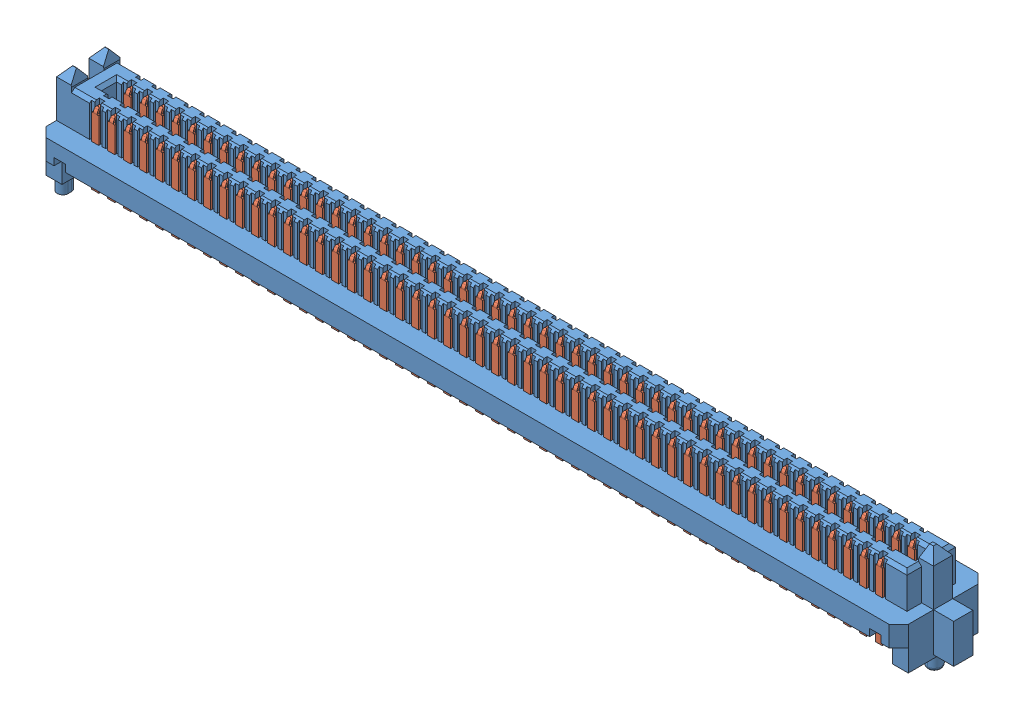
SolidWorks assembly Assem3, configuration Default. Lengths in mm.
Overall size (70.08 8.38 7.06).
5 component instances, 4 part files, 3 mates.
Components (placement in the parent):
- SEAM_50_03_5_L_04_2_A_K_TR-1: SEAM_50_03_5_L_04_2_A_K_TR [Default] at (0 3.3528 0) size (70.08 8.38 7.06)
  - _SEAM_50_03_5_L_04_1_A_K_TR_body_2-1: _SEAM_50_03_5_L_04_1_A_K_TR_body_2 [Default] at origin size (70.08 8.38 7.06)
  - _SEAM_50_03_5_L_04_1_A_K_TR_conn_4-1: _SEAM_50_03_5_L_04_1_A_K_TR_conn_4 [Default] at origin size (67.97 5.75 6.55)
  - _SEAM_K_Pad_04_6-1: _SEAM_K_Pad_04_6 [Default] at (0 2.7432 0) size (5.99 0.13 5.99) (hidden)
  - _SEAM_Triangle_8-1: _SEAM_Triangle_8 [Default] at (32.2834 1.3462 -1.6764) x (-1 0 0) z (0 0 -1) size (1.02 1.27 0.13)
Mates (geometry in assembly coordinates):
- Coincident1: coincident: plane of ? through (32.9692 0 2.7686) normal (0 -1 0)
- Coincident2: coincident: plane of ? through (0 3.3528 0) normal (0 0 1)
- Coincident3: coincident: plane of ? through (0 3.3528 0) normal (1 0 0)
